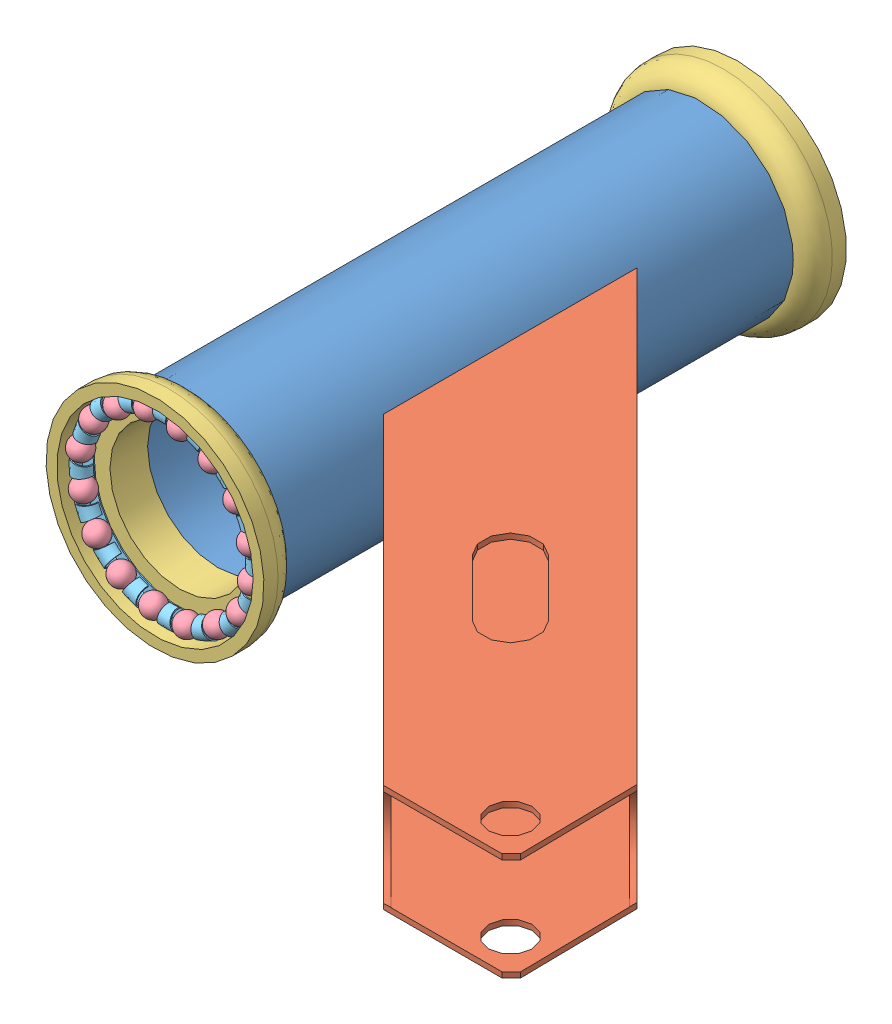
SolidWorks assembly moyeu fourche, configuration Default. Lengths in mm.
Overall size (128.67 65.59 301.45).
43 component instances, 8 part files, 18 mates.
Components (placement in the parent):
- tube moyeu-1: tube moyeu [Default] at (-26.9875 -32.7389 0) size (34 34 95)
- equerre-1: equerre [Default] x (-1 0 0) z (0 1 0) size (83.49 106.89 20)
- cloche roulement-1: cloche roulement [Default] at (-26.9875 -32.7389 0) x (-1 0 0) z (0 1 0) size (40.51 11.62 40.51)
- cloche roulement-2: cloche roulement [Default] at (-26.9875 -32.7389 0) x (0.966442 -0.256884 0) z (0.256884 0.966442 0) size (40.51 11.62 40.51)
- roulement moyeu-1: roulement moyeu [Default] at (-26.9875 -32.7389 -50.7301) x (0.556569 -0.830801 0) z (0.830801 0.556569 0) size (47.2 143.38 46.51)
  - bille-1: bille [Default] at (-16.3235 0.9699 0.0106) x (0.344984 -0.922949 -0.170735) z (0.079352 -0.152572 0.985102) size (4 4 4)
  - cage-1: cage [Default] at origin size (36.4 3.55 36.4)
  - bille-2: bille [Default] at (-6.0395 0.9699 14.7134) size (4 4 4)
  - bille-3: bille [Default] at (-11.4914 0.9699 11.4269) x (0.999917 -0.012878 -0.000163) z (-0.000163 -0.025274 0.999681) size (4 4 4)
  - bille-4: bille [Default] at (-14.8041 0.9699 6.1758) size (4 4 4)
  - bille-5: bille [Default] at (-6.3389 0.9699 -15.2062) size (4 4 4)
  - bille-6: bille [Default] at (6.0934 0.9699 14.7096) size (4 4 4)
  - bille-7: bille [Default] at (14.5997 0.9699 6.138) size (4 4 4)
  - bille-8: bille [Default] at (11.1504 0.9699 11.2899) size (4 4 4)
  - bille-9: bille [Default] at (15.7192 0.9699 -0.0149) size (4 4 4)
  - bille-10: bille [Default] at (-11.4442 0.9699 -11.3654) x (0.89969 -0.394287 -0.187339) z (-0.174381 -0.718048 0.673794) size (4 4 4)
  - bille-11: bille [Default] at (-15.1159 0.9699 -6.0673) size (4 4 4)
  - bille-12: bille [Default] at (-0.1255 0.9699 -16.2249) size (4 4 4)
  - bille-13: bille [Default] at (-0.1376 0.9699 16.1353) size (4 4 4)
  - bille-14: bille [Default] at (14.5011 0.9699 -6.2064) size (4 4 4)
  - bille-15: bille [Default] at (11.268 0.9699 -11.4574) size (4 4 4)
  - bille-16: bille [Default] at (6.0958 0.9699 -14.8703) x (0.607872 0.788579 0.092924) z (0.040029 -0.147312 0.98828) size (4 4 4)
- roulement moyeu-2: roulement moyeu [Default] at (-26.9875 -32.7389 50.7301) x (0.534049 0.845453 0) z (0.845453 -0.534049 0) size (47.2 143.38 46.51)
  - bille-1: bille [Default] at (-16.3235 0.9699 0.0106) x (0.344984 -0.922949 -0.170735) z (0.079352 -0.152572 0.985102) size (4 4 4)
  - cage-1: cage [Default] at origin size (36.4 3.55 36.4)
  - bille-2: bille [Default] at (-6.0395 0.9699 14.7134) size (4 4 4)
  - bille-3: bille [Default] at (-11.4914 0.9699 11.4269) x (0.999917 -0.012878 -0.000163) z (-0.000163 -0.025274 0.999681) size (4 4 4)
  - bille-4: bille [Default] at (-14.8041 0.9699 6.1758) size (4 4 4)
  - bille-5: bille [Default] at (-6.3389 0.9699 -15.2062) size (4 4 4)
  - bille-6: bille [Default] at (6.0934 0.9699 14.7096) size (4 4 4)
  - bille-7: bille [Default] at (14.5997 0.9699 6.138) size (4 4 4)
  - bille-8: bille [Default] at (11.1504 0.9699 11.2899) size (4 4 4)
  - bille-9: bille [Default] at (15.7192 0.9699 -0.0149) size (4 4 4)
  - bille-10: bille [Default] at (-11.4442 0.9699 -11.3654) x (0.89969 -0.394287 -0.187339) z (-0.174381 -0.718048 0.673794) size (4 4 4)
  - bille-11: bille [Default] at (-15.1159 0.9699 -6.0673) size (4 4 4)
  - bille-12: bille [Default] at (-0.1255 0.9699 -16.2249) size (4 4 4)
  - bille-13: bille [Default] at (-0.1376 0.9699 16.1353) size (4 4 4)
  - bille-14: bille [Default] at (14.5011 0.9699 -6.2064) size (4 4 4)
  - bille-15: bille [Default] at (11.268 0.9699 -11.4574) size (4 4 4)
  - bille-16: bille [Default] at (6.0958 0.9699 -14.8703) x (0.607872 0.788579 0.092924) z (0.040029 -0.147312 0.98828) size (4 4 4)
- bouton de manoeuvre-1: bouton de manoeuvre [Default] at (24.7218 -32.7389 16.2093) x (0.707107 0 0.707107) z (0 1 0)
- siège-1: siège [Default] at (30.6791 -50.7389 45.7372) x (0 1 0) z (-0.998072 0 -0.062073) size (7.5 17 17)
- rondelle caoutchouc excentrique-1: rondelle caoutchouc excentrique [Default] at (30.6791 -50.7389 45.7372) x (0 1 0) z (-0.998072 0 -0.062073) size (7.49 15 15)
Mates (geometry in assembly coordinates):
- Sur place1: in place: plane of equerre-1; moOrthogonalPlaneRef_w of equerre-1 through (0 0 0) axis (0 0 1); line of equerre-1 through (1000 -1000 0) axis (0 0 -1); unknown of equerre-1
- Coïncidente1: coincident aligned: plane of equerre-1; plane of assembly
- Coïncidente2: coincident aligned: plane of equerre-1; moOrthogonalPlaneRef_w of assembly
- Coïncidente3: coincident anti-aligned: plane of equerre-1; moOrthogonalPlaneRef_w of assembly
- Sur place2: in place: line of tube moyeu-1 through (-1000 -26.9875 -32.7389) axis (0 0 1); line of cloche roulement-1 through (-1000 -26.9875 -32.7389) axis (0 0 1); line of tube moyeu-1 through (-1000 -26.9875 -32.7389) axis (0 0 1); line of cloche roulement-1 through (-26.9875 -32.7389 0) axis (0 0 1); line of tube moyeu-1 through (-1000 -26.9875 -32.7389) axis (0 0 1); line of cloche roulement-1 through (-1000 -26.9875 -32.7389) axis (0 -1 0); plane of tube moyeu-1 through (-26.9875 -32.7389 0) normal (0 1 0); unknown of cloche roulement-1
- Coïncidente4: coincident aligned: plane of tube moyeu-1; plane of cloche roulement-1
- Coïncidente5: coincident aligned: moOrthogonalPlaneRef_w of tube moyeu-1 through (-26.9875 -32.7389 0) axis (0 0 1); plane of cloche roulement-1
- Coïncidente6: coincident anti-aligned: moOrthogonalPlaneRef_w of tube moyeu-1 through (-1000 -26.9875 -32.7389) axis (0 1 0); plane of cloche roulement-1
- Coaxial1: concentric aligned: cylinder of tube moyeu-1 through (-26.9875 -32.7389 47.5) axis (0 0 -1) radius 17; cylinder of cloche roulement-2 through (-26.9875 -32.7389 0) axis (0 0 -1) radius 15
- Coaxial3: concentric anti-aligned: cylinder of cloche roulement-1 through (-26.9875 -32.7389 0) axis (0 0 1) radius 13; cylinder of roulement moyeu-1/cage-1 through (-26.9875 -32.7389 -58.3742) axis (0 0 -1) radius 18.2
- Coaxial4: concentric anti-aligned: cylinder of tube moyeu-1 through (-26.9875 -32.7389 47.5) axis (0 0 -1) radius 17; cylinder of roulement moyeu-2/cage-1 through (-26.9875 -32.7389 58.3742) axis (0 0 1) radius 18.2
- Coïncidente8: coincident anti-aligned: plane of cloche roulement-1 through (-9.314 -32.7389 -49.5) normal (0 0 -1); plane of roulement moyeu-1/cage-1 through (-35.8463 -19.5152 -49.5) normal (0 0 1)
- Coïncidente9: coincident anti-aligned: plane of cloche roulement-2 through (-44.0679 -28.1989 49.5) normal (0 0 1); plane of roulement moyeu-2/cage-1 through (-35.4879 -46.1959 49.5) normal (0 0 -1)
- Coïncidente10: coincident anti-aligned: plane of tube moyeu-1 through (-26.9875 -32.7389 47.5) normal (0 0 1); plane of cloche roulement-2 through (-41.4841 -28.8857 47.5) normal (0 0 -1)
- Sur place4: in place: line of ? through (29.7144 -50.7389 46.7019) axis (0.484935 0 0.87455); line of ? through (29.7144 -50.7389 46.7019) axis (0.484935 0 0.87455); line of ? through (29.7144 -50.7389 46.7019) axis (0.484935 0 0.87455); line of ? through (29.7144 -50.7389 46.7019) axis (-0.87455 0 0.484935); line of ? through (29.7144 -50.7389 46.7019) axis (0.484935 0 0.87455); line of ? through (29.7144 -50.7389 46.7019) axis (0 1 0); plane of ? through (30.6791 -50.7389 45.7372) normal (-0.998072 0 -0.062073); unknown of ?
- Coïncidente17: coincident aligned: plane of siège-1; plane of rondelle caoutchouc excentrique-1
- Coïncidente18: coincident aligned: moOrthogonalPlaneRef_w of siège-1 through (30.6791 -50.7389 45.7372) axis (0.062073 0 -0.998072); plane of rondelle caoutchouc excentrique-1
- Coïncidente19: coincident anti-aligned: moOrthogonalPlaneRef_w of siège-1 through (30.6791 -50.7389 45.7372) axis (0 -1 0); plane of rondelle caoutchouc excentrique-1
